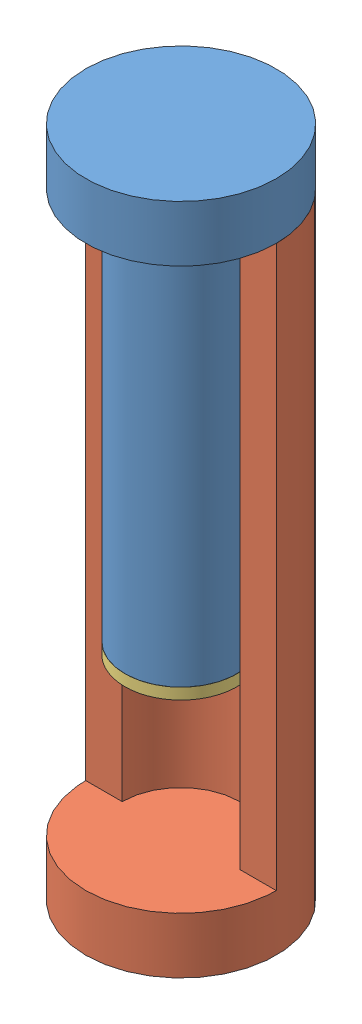
SolidWorks assembly JumpingSumo, configuration Défaut. Lengths in mm.
Overall size (46.17 120 46.17).
3 component instances, 3 part files, 2 mates.
Components (placement in the parent):
- pieceInterieure-1: pieceInterieure [Défaut] at (-22.8763 -86.6449 117.1103) x (0.481503 0 -0.876444) z (0.876444 0 0.481503) size (34 80 34)
- pieceExterieure-2: pieceExterieure [Défaut] at (-22.8763 -116.6449 117.1103) size (34 110 34)
- pieceContactRessort-1: pieceContactRessort [Défaut] at (-22.8763 -88.6449 117.1103) x (0.961413 0 -0.275107) z (0.275107 0 0.961413) size (20 2 20)
Mates (geometry in assembly coordinates):
- Coaxiale4: concentric: cylinder of pieceInterieure-1 through (-22.8763 -16.6449 117.1103) axis (0 -1 0) radius 10; cylinder of pieceExterieure-2 through (-22.8763 -16.6449 117.1103) axis (0 -1 0) radius 10.5
- Coaxiale5: concentric: cylinder of pieceExterieure-2 through (-22.8763 -16.6449 117.1103) axis (0 -1 0) radius 10.5; circle of pieceContactRessort-1
